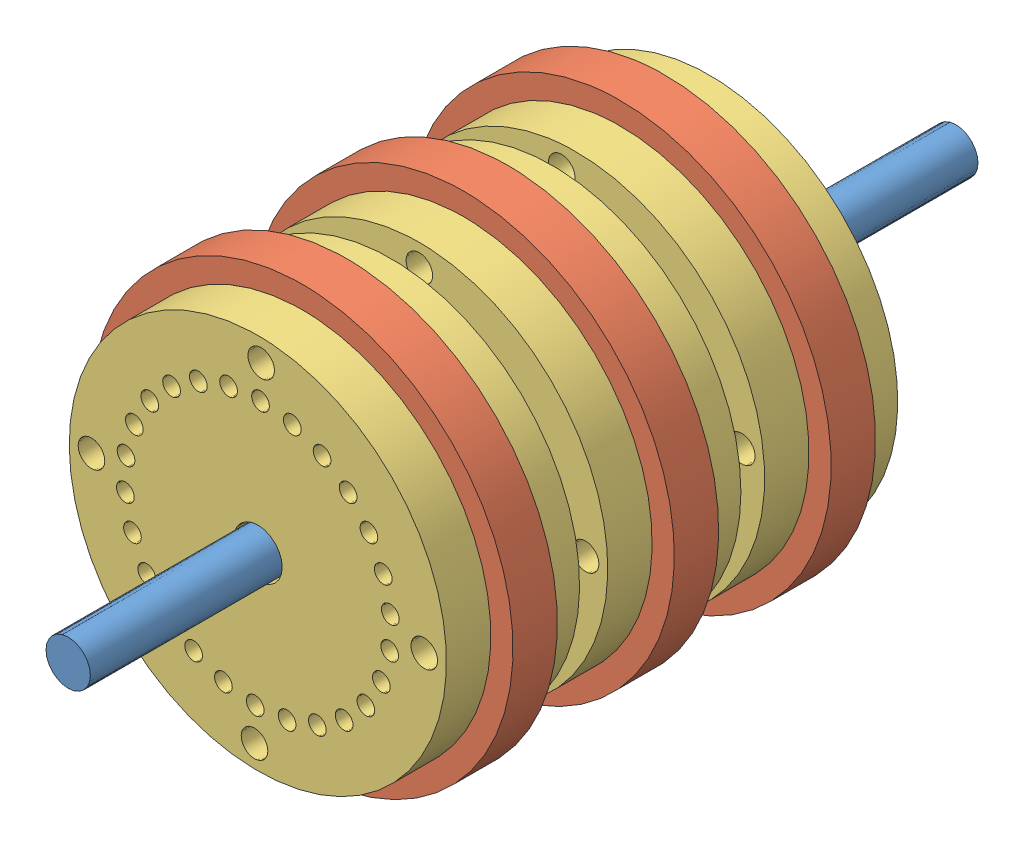
SolidWorks assembly Assemblage2, configuration Défaut. Lengths in mm.
Overall size (10.28 10.28 20).
13 component instances, 3 part files, 3 mates.
Components (placement in the parent):
- tige 1cd-1: tige 1cd [Défaut] at (-0.0168 -0.0084 10) size (1 1 20)
- assemblage rotor-1: assemblage rotor [Défaut] at (-0.0168 -0.0084 13.4414) x (0.996289 0.086067 0) z (0 0 1) size (9.5 9.5 3)
  - pignon sans pigon-1: pignon sans pigon [Défaut] at (0 0 3.1162) x (0 1 0) z (0 0 1) size (9.5 9.5 1)
  - rotor-1: rotor [Défaut] at (0 0 5.1162) x (1 0 0) z (0 1 0) size (8.5 1 8.5)
  - rotor-2: rotor [Défaut] at (0 0 3.1162) x (0 1 0) z (-1 0 0) size (8.5 1 8.5)
- assemblage rotor-2: assemblage rotor [Défaut] at (-0.0168 -0.0084 16.9754) x (1 -0.000875 0) z (0 0 1) size (9.5 9.5 3)
  - pignon sans pigon-1: pignon sans pigon [Défaut] at (0 0 3.1162) x (0 1 0) z (0 0 1) size (9.5 9.5 1)
  - rotor-1: rotor [Défaut] at (0 0 5.1162) x (1 0 0) z (0 1 0) size (8.5 1 8.5)
  - rotor-2: rotor [Défaut] at (0 0 3.1162) x (0 1 0) z (-1 0 0) size (8.5 1 8.5)
- assemblage rotor-3: assemblage rotor [Défaut] at (-0.0168 -0.0084 20.6104) x (0.999799 -0.020046 0) z (0 0 1) size (9.5 9.5 3)
  - pignon sans pigon-1: pignon sans pigon [Défaut] at (0 0 3.1162) x (0 1 0) z (0 0 1) size (9.5 9.5 1)
  - rotor-1: rotor [Défaut] at (0 0 5.1162) x (1 0 0) z (0 1 0) size (8.5 1 8.5)
  - rotor-2: rotor [Défaut] at (0 0 3.1162) x (0 1 0) z (-1 0 0) size (8.5 1 8.5)
Mates (geometry in assembly coordinates):
- Coaxiale1: concentric anti-aligned: cylinder of tige 1cd-1 through (-0.0168 -0.0084 30) axis (0 0 -1) radius 0.5; cylinder of assemblage rotor-1/rotor-2 through (-0.0168 -0.0084 15.5576) axis (0 0 1) radius 0.55
- Coaxiale3: concentric anti-aligned: cylinder of tige 1cd-1 through (-0.0168 -0.0084 30) axis (0 0 -1) radius 0.5; cylinder of assemblage rotor-2/rotor-1 through (-0.0168 -0.0084 21.0916) axis (0 0 1) radius 0.55
- Coaxiale4: concentric anti-aligned: cylinder of tige 1cd-1 through (-0.0168 -0.0084 30) axis (0 0 -1) radius 0.5; cylinder of assemblage rotor-3/rotor-2 through (-0.0168 -0.0084 22.7265) axis (0 0 1) radius 0.55
